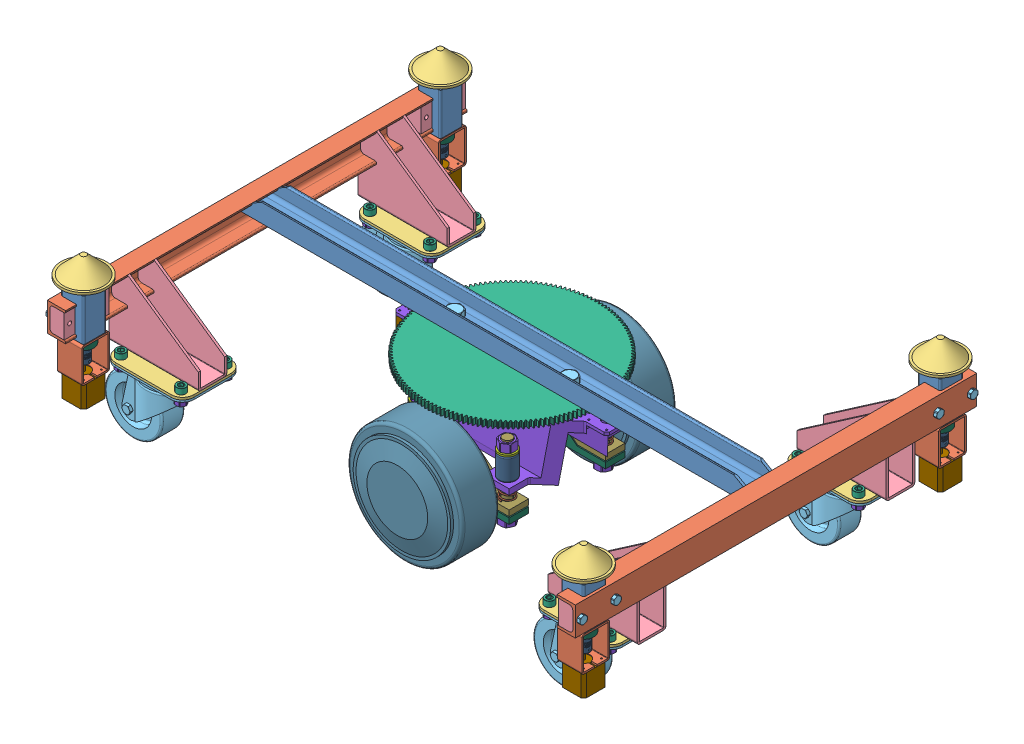
SolidWorks assembly ТП.SH21(K2).00 - Концепт 2, configuration 00. Lengths in mm.
Overall size (950 309 700).
181 component instances, 34 part files, 41 mates.
Components (placement in the parent):
- ТП.SH21(K2).01.00 - Каркас несущий К2-1: ТП.SH21(K2).01.00 - Каркас несущий К2 [00] at (0 265 0) size (950 309 700)
  - ТП.SH21(K2).01.01.00 - Рама силовая (К2)-1: ТП.SH21(K2).01.01.00 - Рама силовая (К2) [00] at origin size (920.8 129.01 700)
    - ТП.SH21(K2).01.01.01 - Хребет продольный-1: ТП.SH21(K2).01.01.01 - Хребет продольный [--] at origin size (912 32 50)
    - ТП.SH21(K2).01.01.02.00 - Балка несущая-1: ТП.SH21(K2).01.01.02.00 - Балка несущая [00] at (-456 -42.75 0) size (155.33 119.25 700)
      - ТП.SH21(K1).01.02 - Поперечина-1: ТП.SH21(K1).01.02 - Поперечина [--] at origin size (32 50 700)
      - ТП.SH21(K2).01.01.02.01.00 - Кронштейн ленивца-1: ТП.SH21(K2).01.01.02.01.00 - Кронштейн ленивца [00] at (82.4347 -94.25 217) size (155.33 119.25 105)
        - ТП.SH21(K1).01.01.02 - Опора ленивца-1: ТП.SH21(K1).01.01.02 - Опора ленивца [--] at origin size (137 4 105)
        - ТП.SH21(K2).01.01.02.01.01 - Касынка кронштейна ленивца-1: ТП.SH21(K2).01.01.02.01.01 - Касынка кронштейна ленивца [--] at (0 4 0) size (155.33 115.25 50)
      - ТП.SH21(K2).01.01.02.01.00 - Кронштейн ленивца-2: ТП.SH21(K2).01.01.02.01.00 - Кронштейн ленивца [00] at (82.4347 -94.25 -217) size (155.33 119.25 105)
        - ТП.SH21(K1).01.01.02 - Опора ленивца-1: ТП.SH21(K1).01.01.02 - Опора ленивца [--] at origin size (137 4 105)
        - ТП.SH21(K2).01.01.02.01.01 - Касынка кронштейна ленивца-1: ТП.SH21(K2).01.01.02.01.01 - Касынка кронштейна ленивца [--] at (0 4 0) size (155.33 115.25 50)
    - ТП.SH21(K2).01.01.02.00 - Балка несущая-2: ТП.SH21(K2).01.01.02.00 - Балка несущая [00] at (456 -42.75 0) x (-1 0 0) z (0 0 -1) size (155.33 119.25 700)
      - ТП.SH21(K1).01.02 - Поперечина-1: ТП.SH21(K1).01.02 - Поперечина [--] at origin size (32 50 700)
      - ТП.SH21(K2).01.01.02.01.00 - Кронштейн ленивца-1: ТП.SH21(K2).01.01.02.01.00 - Кронштейн ленивца [00] at (82.4347 -94.25 217) size (155.33 119.25 105)
        - ТП.SH21(K1).01.01.02 - Опора ленивца-1: ТП.SH21(K1).01.01.02 - Опора ленивца [--] at origin size (137 4 105)
        - ТП.SH21(K2).01.01.02.01.01 - Касынка кронштейна ленивца-1: ТП.SH21(K2).01.01.02.01.01 - Касынка кронштейна ленивца [--] at (0 4 0) size (155.33 115.25 50)
      - ТП.SH21(K2).01.01.02.01.00 - Кронштейн ленивца-2: ТП.SH21(K2).01.01.02.01.00 - Кронштейн ленивца [00] at (82.4347 -94.25 -217) size (155.33 119.25 105)
        - ТП.SH21(K1).01.01.02 - Опора ленивца-1: ТП.SH21(K1).01.01.02 - Опора ленивца [--] at origin size (137 4 105)
        - ТП.SH21(K2).01.01.02.01.01 - Касынка кронштейна ленивца-1: ТП.SH21(K2).01.01.02.01.01 - Касынка кронштейна ленивца [--] at (0 4 0) size (155.33 115.25 50)
  - АЗ - Колесо ленивец - Tente Alpha 3470 ITP 100 P63-1: АЗ - Колесо ленивец - Tente Alpha 3470 ITP 100 P63 [По умолчанию] at (-373.5653 -137 217) size (168.5 128 105)
  - АЗ - Колесо ленивец - Tente Alpha 3470 ITP 100 P63-2: АЗ - Колесо ленивец - Tente Alpha 3470 ITP 100 P63 [По умолчанию] at (373.5653 -137 217) size (168.5 128 105)
  - АЗ - Колесо ленивец - Tente Alpha 3470 ITP 100 P63-3: АЗ - Колесо ленивец - Tente Alpha 3470 ITP 100 P63 [По умолчанию] at (373.5653 -137 -217) size (168.5 128 105)
  - АЗ - Колесо ленивец - Tente Alpha 3470 ITP 100 P63-4: АЗ - Колесо ленивец - Tente Alpha 3470 ITP 100 P63 [По умолчанию] at (-373.5653 -137 -217) size (168.5 128 105)
  - Винты с цилиндрической головкой (ГОСТ 11738-84)-1: Винты с цилиндрической головкой (ГОСТ 11738-84) [Винт М10-(6g)x20 ГОСТ 11738-84] at (-426.0653 -133 255.75) x (0.408379 0 0.912812) z (0 1 0) size (16 16 30.28)
  - Шайбы (ГОСТ 11371-78)-1: Шайбы (ГОСТ 11371-78) [Шайба 10 ГОСТ 11371-78] at (-426.0653 -141.5 255.75) x (0 -1 0) z (0.195759 0 0.980652) size (2 20 20)
  - Гайка (ГОСТ ISO 4032-2014)-1: Гайка (ГОСТ ISO 4032-2014) [Гайка М10 (ГОСТ ISO 4032)] at (-426.0653 -146.7 255.75) x (0.781361 0 0.624079) z (0 1 0) size (16 17.77 8.4)
  - Гайка (ГОСТ ISO 4032-2014)-2: Гайка (ГОСТ ISO 4032-2014) [Гайка М10 (ГОСТ ISO 4032)] at (-321.0653 -146.7 255.75) x (0.884972 0 0.465645) z (0 1 0) size (16 17.77 8.4)
  - Шайбы (ГОСТ 11371-78)-2: Шайбы (ГОСТ 11371-78) [Шайба 10 ГОСТ 11371-78] at (-321.0653 -141.5 255.75) x (0 -1 0) z (0.37706 0 0.926189) size (2 20 20)
  - Винты с цилиндрической головкой (ГОСТ 11738-84)-2: Винты с цилиндрической головкой (ГОСТ 11738-84) [Винт М10-(6g)x20 ГОСТ 11738-84] at (-321.0653 -133 255.75) x (0.573086 0 0.819496) z (0 1 0) size (16 16 30.28)
  - Гайка (ГОСТ ISO 4032-2014)-3: Гайка (ГОСТ ISO 4032-2014) [Гайка М10 (ГОСТ ISO 4032)] at (-321.0653 -146.7 178.25) x (0.964544 0 0.263921) z (0 1 0) size (16 17.77 8.4)
  - Шайбы (ГОСТ 11371-78)-3: Шайбы (ГОСТ 11371-78) [Шайба 10 ГОСТ 11371-78] at (-321.0653 -141.5 178.25) x (0 -1 0) z (0.567856 0 0.823128) size (2 20 20)
  - Винты с цилиндрической головкой (ГОСТ 11738-84)-3: Винты с цилиндрической головкой (ГОСТ 11738-84) [Винт М10-(6g)x20 ГОСТ 11738-84] at (-321.0653 -133 178.25) x (0.736272 0 0.676686) z (0 1 0) size (16 16 30.28)
  - Гайка (ГОСТ ISO 4032-2014)-4: Гайка (ГОСТ ISO 4032-2014) [Гайка М10 (ГОСТ ISO 4032)] at (-426.0653 -146.7 178.25) x (0.999536 0 0.030446) z (0 1 0) size (16 17.77 8.4)
  - Шайбы (ГОСТ 11371-78)-4: Шайбы (ГОСТ 11371-78) [Шайба 10 ГОСТ 11371-78] at (-426.0653 -141.5 178.25) x (0 -1 0) z (0.744998 0 0.667066) size (2 20 20)
  - Винты с цилиндрической головкой (ГОСТ 11738-84)-4: Винты с цилиндрической головкой (ГОСТ 11738-84) [Винт М10-(6g)x20 ГОСТ 11738-84] at (-426.0653 -133 178.25) x (0.874391 0 0.485223) z (0 1 0) size (16 16 30.28)
  - Гайка (ГОСТ ISO 4032-2014)-5: Гайка (ГОСТ ISO 4032-2014) [Гайка М10 (ГОСТ ISO 4032)] at (-426.0653 -146.7 -178.25) x (0.97789 0 -0.209118) z (0 1 0) size (16 17.77 8.4)
  - Шайбы (ГОСТ 11371-78)-5: Шайбы (ГОСТ 11371-78) [Шайба 10 ГОСТ 11371-78] at (-426.0653 -141.5 -178.25) x (0 -1 0) z (0.882737 0 0.469867) size (2 20 20)
  - Винты с цилиндрической головкой (ГОСТ 11738-84)-5: Винты с цилиндрической головкой (ГОСТ 11738-84) [Винт М10-(6g)x20 ГОСТ 11738-84] at (-426.0653 -133 -178.25) x (0.964963 0 0.262386) z (0 1 0) size (16 16 30.28)
  - Гайка (ГОСТ ISO 4032-2014)-6: Гайка (ГОСТ ISO 4032-2014) [Гайка М10 (ГОСТ ISO 4032)] at (-321.0653 -146.7 -178.25) x (0.905941 0 -0.423405) z (0 1 0) size (16 17.77 8.4)
  - Шайбы (ГОСТ 11371-78)-6: Шайбы (ГОСТ 11371-78) [Шайба 10 ГОСТ 11371-78] at (-321.0653 -141.5 -178.25) x (0 -1 0) z (0.965715 0 0.259604) size (2 20 20)
  - Винты с цилиндрической головкой (ГОСТ 11738-84)-6: Винты с цилиндрической головкой (ГОСТ 11738-84) [Винт М10-(6g)x20 ГОСТ 11738-84] at (-321.0653 -133 -178.25) x (0.999241 0 0.038957) z (0 1 0) size (16 16 30.28)
  - Гайка (ГОСТ ISO 4032-2014)-7: Гайка (ГОСТ ISO 4032-2014) [Гайка М10 (ГОСТ ISO 4032)] at (-426.0653 -146.7 -255.75) x (0.807744 0 -0.589534) z (0 1 0) size (16 17.77 8.4)
  - Шайбы (ГОСТ 11371-78)-7: Шайбы (ГОСТ 11371-78) [Шайба 10 ГОСТ 11371-78] at (-426.0653 -141.5 -255.75) x (0 -1 0) z (0.997598 0 0.069276) size (2 20 20)
  - Винты с цилиндрической головкой (ГОСТ 11738-84)-7: Винты с цилиндрической головкой (ГОСТ 11738-84) [Винт М10-(6g)x20 ГОСТ 11738-84] at (-426.0653 -133 -255.75) x (0.988117 0 -0.153703) z (0 1 0) size (16 16 30.28)
  - Гайка (ГОСТ ISO 4032-2014)-8: Гайка (ГОСТ ISO 4032-2014) [Гайка М10 (ГОСТ ISO 4032)] at (-321.0653 -146.7 -255.75) x (0.713458 0 -0.700698) z (0 1 0) size (16 17.77 8.4)
  - Шайбы (ГОСТ 11371-78)-8: Шайбы (ГОСТ 11371-78) [Шайба 10 ГОСТ 11371-78] at (-321.0653 -141.5 -255.75) x (0 -1 0) z (0.997071 0 -0.076488) size (2 20 20)
  - Винты с цилиндрической головкой (ГОСТ 11738-84)-8: Винты с цилиндрической головкой (ГОСТ 11738-84) [Винт М10-(6g)x20 ГОСТ 11738-84] at (-321.0653 -133 -255.75) x (0.955275 0 -0.295719) z (0 1 0) size (16 16 30.28)
  - Гайка (ГОСТ ISO 4032-2014)-9: Гайка (ГОСТ ISO 4032-2014) [Гайка М10 (ГОСТ ISO 4032)] at (321.0653 -146.7 255.75) x (0.647527 0 -0.762043) z (0 1 0) size (16 17.77 8.4)
  - Шайбы (ГОСТ 11371-78)-9: Шайбы (ГОСТ 11371-78) [Шайба 10 ГОСТ 11371-78] at (321.0653 -141.5 255.75) x (0 -1 0) z (0.986146 0 -0.165879) size (2 20 20)
  - Винты с цилиндрической головкой (ГОСТ 11738-84)-9: Винты с цилиндрической головкой (ГОСТ 11738-84) [Винт М10-(6g)x20 ГОСТ 11738-84] at (321.0653 -133 255.75) x (0.924797 0 -0.380462) z (0 1 0) size (16 16 30.28)
  - Гайка (ГОСТ ISO 4032-2014)-10: Гайка (ГОСТ ISO 4032-2014) [Гайка М10 (ГОСТ ISO 4032)] at (426.0653 -146.7 255.75) x (0.624079 0 -0.781361) z (0 1 0) size (16 17.77 8.4)
  - Шайбы (ГОСТ 11371-78)-10: Шайбы (ГОСТ 11371-78) [Шайба 10 ГОСТ 11371-78] at (426.0653 -141.5 255.75) x (0 -1 0) z (0.980652 0 -0.195759) size (2 20 20)
  - Винты с цилиндрической головкой (ГОСТ 11738-84)-10: Винты с цилиндрической головкой (ГОСТ 11738-84) [Винт М10-(6g)x20 ГОСТ 11738-84] at (426.0653 -133 255.75) x (0.912812 0 -0.408379) z (0 1 0) size (16 16 30.28)
  - Гайка (ГОСТ ISO 4032-2014)-11: Гайка (ГОСТ ISO 4032-2014) [Гайка М10 (ГОСТ ISO 4032)] at (321.0653 -146.7 178.25) x (0.647527 0 -0.762043) z (0 1 0) size (16 17.77 8.4)
  - Шайбы (ГОСТ 11371-78)-11: Шайбы (ГОСТ 11371-78) [Шайба 10 ГОСТ 11371-78] at (321.0653 -141.5 178.25) x (0 -1 0) z (0.986146 0 -0.165879) size (2 20 20)
  - Винты с цилиндрической головкой (ГОСТ 11738-84)-11: Винты с цилиндрической головкой (ГОСТ 11738-84) [Винт М10-(6g)x20 ГОСТ 11738-84] at (321.0653 -133 178.25) x (0.924797 0 -0.380462) z (0 1 0) size (16 16 30.28)
  - Гайка (ГОСТ ISO 4032-2014)-12: Гайка (ГОСТ ISO 4032-2014) [Гайка М10 (ГОСТ ISO 4032)] at (426.0653 -146.7 178.25) x (0.713458 0 -0.700698) z (0 1 0) size (16 17.77 8.4)
  - Шайбы (ГОСТ 11371-78)-12: Шайбы (ГОСТ 11371-78) [Шайба 10 ГОСТ 11371-78] at (426.0653 -141.5 178.25) x (0 -1 0) z (0.997071 0 -0.076488) size (2 20 20)
  - Винты с цилиндрической головкой (ГОСТ 11738-84)-12: Винты с цилиндрической головкой (ГОСТ 11738-84) [Винт М10-(6g)x20 ГОСТ 11738-84] at (426.0653 -133 178.25) x (0.955275 0 -0.295719) z (0 1 0) size (16 16 30.28)
  - Гайка (ГОСТ ISO 4032-2014)-13: Гайка (ГОСТ ISO 4032-2014) [Гайка М10 (ГОСТ ISO 4032)] at (321.0653 -146.7 -178.25) x (0.807744 0 -0.589534) z (0 1 0) size (16 17.77 8.4)
  - Шайбы (ГОСТ 11371-78)-13: Шайбы (ГОСТ 11371-78) [Шайба 10 ГОСТ 11371-78] at (321.0653 -141.5 -178.25) x (0 -1 0) z (0.997598 0 0.069276) size (2 20 20)
  - Винты с цилиндрической головкой (ГОСТ 11738-84)-13: Винты с цилиндрической головкой (ГОСТ 11738-84) [Винт М10-(6g)x20 ГОСТ 11738-84] at (321.0653 -133 -178.25) x (0.988117 0 -0.153703) z (0 1 0) size (16 16 30.28)
  - Гайка (ГОСТ ISO 4032-2014)-14: Гайка (ГОСТ ISO 4032-2014) [Гайка М10 (ГОСТ ISO 4032)] at (426.0653 -146.7 -178.25) x (0.905941 0 -0.423405) z (0 1 0) size (16 17.77 8.4)
  - Шайбы (ГОСТ 11371-78)-14: Шайбы (ГОСТ 11371-78) [Шайба 10 ГОСТ 11371-78] at (426.0653 -141.5 -178.25) x (0 -1 0) z (0.965715 0 0.259604) size (2 20 20)
  - Винты с цилиндрической головкой (ГОСТ 11738-84)-14: Винты с цилиндрической головкой (ГОСТ 11738-84) [Винт М10-(6g)x20 ГОСТ 11738-84] at (426.0653 -133 -178.25) x (0.999241 0 0.038957) z (0 1 0) size (16 16 30.28)
  - Гайка (ГОСТ ISO 4032-2014)-15: Гайка (ГОСТ ISO 4032-2014) [Гайка М10 (ГОСТ ISO 4032)] at (321.0653 -146.7 -255.75) x (0.97789 0 -0.209118) z (0 1 0) size (16 17.77 8.4)
  - Шайбы (ГОСТ 11371-78)-15: Шайбы (ГОСТ 11371-78) [Шайба 10 ГОСТ 11371-78] at (321.0653 -141.5 -255.75) x (0 -1 0) z (0.882737 0 0.469867) size (2 20 20)
  - Винты с цилиндрической головкой (ГОСТ 11738-84)-15: Винты с цилиндрической головкой (ГОСТ 11738-84) [Винт М10-(6g)x20 ГОСТ 11738-84] at (321.0653 -133 -255.75) x (0.964963 0 0.262386) z (0 1 0) size (16 16 30.28)
  - Гайка (ГОСТ ISO 4032-2014)-16: Гайка (ГОСТ ISO 4032-2014) [Гайка М10 (ГОСТ ISO 4032)] at (426.0653 -146.7 -255.75) x (0.999536 0 0.030446) z (0 1 0) size (16 17.77 8.4)
  - Шайбы (ГОСТ 11371-78)-16: Шайбы (ГОСТ 11371-78) [Шайба 10 ГОСТ 11371-78] at (426.0653 -141.5 -255.75) x (0 -1 0) z (0.744998 0 0.667066) size (2 20 20)
  - Винты с цилиндрической головкой (ГОСТ 11738-84)-16: Винты с цилиндрической головкой (ГОСТ 11738-84) [Винт М10-(6g)x20 ГОСТ 11738-84] at (426.0653 -133 -255.75) x (0.874391 0 0.485223) z (0 1 0) size (16 16 30.28)
  - ТП.SH21(K1).02.00 - Линейный движитель-1: ТП.SH21(K1).02.00 - Линейный движитель [00] at (-436 -133 311) x (1 0 0) z (0 1 0) size (78 78 215)
    - 17HS4401 (Nema17)-1: 17HS4401 (Nema17) [--] at origin size (42.3 42.3 63.5)
    - Муфта гибкая-1: Муфта гибкая [--] at (0 0 42.25) size (20 20 26)
    - Винт CS М12х2х150-1: Винт CS М12х2х150 [--] at (0 0 133) x (0.999367 0.035585 0) z (0 0 1) size (12 12.62 100)
    - ТП.SH21(K1).02.01 - Упор винта-1: ТП.SH21(K1).02.01 - Упор винта [--] at (0 0 57.25) size (14 14 13)
    - Подшипник упорный 8100-1: Подшипник упорный 8100 [--] at (0 0 48.25) x (1 0 0) z (0 -1 0) size (24 9 24)
    - Стопор внутренний до 165мм (ГОСТ 13943-86)-1: Стопор внутренний до 165мм (ГОСТ 13943-86) [Кольцо 24] at (0 0 47.05) size (25.5 24.21 1.2)
    - ТП.SH21(K1).02.02 - Обойма под 8100-1: ТП.SH21(K1).02.02 - Обойма под 8100 [--] at (0 0 48.25) size (35 35 16.2)
    - Гайка DCM12-1: Гайка DCM12 [Доработка] at (0 0 64.25) x (0 0 1) z (-0.707107 -0.707107 0) size (30.72 41.36 41.36)
    - ТП.SH21(K1).02.03 - Профильная труба 35х35х2-1: ТП.SH21(K1).02.03 - Профильная труба 35х35х2 [--] at (0 0 74.25) size (35 35 68.75)
    - ТП.SH21(K1).02.04 - Заглушка35х35-1: ТП.SH21(K1).02.04 - Заглушка35х35 [--] at (0 0 70.25) size (35 35 4)
    - ТП.SH21(K1).02.05 - Профильная труба 40х40х2-1: ТП.SH21(K1).02.05 - Профильная труба 40х40х2 [--] at (0 0 60.25) size (40 40 72.75)
    - ТП.SH21(K1).02.06 - Заглушка 40х40-1: ТП.SH21(K1).02.06 - Заглушка 40х40 [--] at (0 0 60.25) size (42.3 48.3 60.25)
    - ТП.SH21(K1).02.07 - Уловитель-1: ТП.SH21(K1).02.07 - Уловитель [--] at (0 0 143) size (78 78 39)
    - ТП.SH21(K1).02.08 - Фиксатор-1: ТП.SH21(K1).02.08 - Фиксатор [--] at (-20 -20 60.25) x (0 1 0) z (1 0 0) size (19 41.2 25.1)
    - ТП.SH21(K1).02.08 - Фиксатор-2: ТП.SH21(K1).02.08 - Фиксатор [--] at (-20 39 60.25) x (0 1 0) z (1 0 0) size (19 41.2 25.1)
  - Болты с шестигранной головкой кт.В (ГОСТ 7798-70)-1: Болты с шестигранной головкой кт.В (ГОСТ 7798-70) [Болт М8-6gx25(S13) ГОСТ 7798-77] at (-460.4 -42.75 340.5) size (30.3 14.2 13)
  - Болты с шестигранной головкой кт.В (ГОСТ 7798-70)-2: Болты с шестигранной головкой кт.В (ГОСТ 7798-70) [Болт М8-6gx25(S13) ГОСТ 7798-77] at (-460.4 -42.75 281.5) x (1 0 0) z (0 -0.158553 0.987351) size (30.3 14.2 13)
  - ТП.SH21(K1).02.00 - Линейный движитель-2: ТП.SH21(K1).02.00 - Линейный движитель [00] at (-436 -133 -311) x (1 0 0) z (0 1 0) size (78 78 215)
    - 17HS4401 (Nema17)-1: 17HS4401 (Nema17) [--] at origin size (42.3 42.3 63.5)
    - Муфта гибкая-1: Муфта гибкая [--] at (0 0 42.25) size (20 20 26)
    - Винт CS М12х2х150-1: Винт CS М12х2х150 [--] at (0 0 133) x (0.999367 0.035585 0) z (0 0 1) size (12 12.62 100)
    - ТП.SH21(K1).02.01 - Упор винта-1: ТП.SH21(K1).02.01 - Упор винта [--] at (0 0 57.25) size (14 14 13)
    - Подшипник упорный 8100-1: Подшипник упорный 8100 [--] at (0 0 48.25) x (1 0 0) z (0 -1 0) size (24 9 24)
    - Стопор внутренний до 165мм (ГОСТ 13943-86)-1: Стопор внутренний до 165мм (ГОСТ 13943-86) [Кольцо 24] at (0 0 47.05) size (25.5 24.21 1.2)
    - ТП.SH21(K1).02.02 - Обойма под 8100-1: ТП.SH21(K1).02.02 - Обойма под 8100 [--] at (0 0 48.25) size (35 35 16.2)
    - Гайка DCM12-1: Гайка DCM12 [Доработка] at (0 0 64.25) x (0 0 1) z (-0.707107 -0.707107 0) size (30.72 41.36 41.36)
    - ТП.SH21(K1).02.03 - Профильная труба 35х35х2-1: ТП.SH21(K1).02.03 - Профильная труба 35х35х2 [--] at (0 0 74.25) size (35 35 68.75)
    - ТП.SH21(K1).02.04 - Заглушка35х35-1: ТП.SH21(K1).02.04 - Заглушка35х35 [--] at (0 0 70.25) size (35 35 4)
    - ТП.SH21(K1).02.05 - Профильная труба 40х40х2-1: ТП.SH21(K1).02.05 - Профильная труба 40х40х2 [--] at (0 0 60.25) size (40 40 72.75)
    - ТП.SH21(K1).02.06 - Заглушка 40х40-1: ТП.SH21(K1).02.06 - Заглушка 40х40 [--] at (0 0 60.25) size (42.3 48.3 60.25)
    - ТП.SH21(K1).02.07 - Уловитель-1: ТП.SH21(K1).02.07 - Уловитель [--] at (0 0 143) size (78 78 39)
    - ТП.SH21(K1).02.08 - Фиксатор-1: ТП.SH21(K1).02.08 - Фиксатор [--] at (-20 -20 60.25) x (0 1 0) z (1 0 0) size (19 41.2 25.1)
    - ТП.SH21(K1).02.08 - Фиксатор-2: ТП.SH21(K1).02.08 - Фиксатор [--] at (-20 39 60.25) x (0 1 0) z (1 0 0) size (19 41.2 25.1)
  - Болты с шестигранной головкой кт.В (ГОСТ 7798-70)-4: Болты с шестигранной головкой кт.В (ГОСТ 7798-70) [Болт М8-6gx25(S13) ГОСТ 7798-77] at (-460.4 -42.75 -281.5) size (30.3 14.2 13)
  - Болты с шестигранной головкой кт.В (ГОСТ 7798-70)-5: Болты с шестигранной головкой кт.В (ГОСТ 7798-70) [Болт М8-6gx25(S13) ГОСТ 7798-77] at (-460.4 -42.75 -340.5) x (1 0 0) z (0 -0.158553 0.987351) size (30.3 14.2 13)
  - ТП.SH21(K1).02.00 - Линейный движитель-5: ТП.SH21(K1).02.00 - Линейный движитель [00] at (436 -133 311) x (-1 0 0) z (0 1 0) size (78 78 215)
    - 17HS4401 (Nema17)-1: 17HS4401 (Nema17) [--] at origin size (42.3 42.3 63.5)
    - Муфта гибкая-1: Муфта гибкая [--] at (0 0 42.25) size (20 20 26)
    - Винт CS М12х2х150-1: Винт CS М12х2х150 [--] at (0 0 133) x (0.999367 0.035585 0) z (0 0 1) size (12 12.62 100)
    - ТП.SH21(K1).02.01 - Упор винта-1: ТП.SH21(K1).02.01 - Упор винта [--] at (0 0 57.25) size (14 14 13)
    - Подшипник упорный 8100-1: Подшипник упорный 8100 [--] at (0 0 48.25) x (1 0 0) z (0 -1 0) size (24 9 24)
    - Стопор внутренний до 165мм (ГОСТ 13943-86)-1: Стопор внутренний до 165мм (ГОСТ 13943-86) [Кольцо 24] at (0 0 47.05) size (25.5 24.21 1.2)
    - ТП.SH21(K1).02.02 - Обойма под 8100-1: ТП.SH21(K1).02.02 - Обойма под 8100 [--] at (0 0 48.25) size (35 35 16.2)
    - Гайка DCM12-1: Гайка DCM12 [Доработка] at (0 0 64.25) x (0 0 1) z (-0.707107 -0.707107 0) size (30.72 41.36 41.36)
    - ТП.SH21(K1).02.03 - Профильная труба 35х35х2-1: ТП.SH21(K1).02.03 - Профильная труба 35х35х2 [--] at (0 0 74.25) size (35 35 68.75)
    - ТП.SH21(K1).02.04 - Заглушка35х35-1: ТП.SH21(K1).02.04 - Заглушка35х35 [--] at (0 0 70.25) size (35 35 4)
    - ТП.SH21(K1).02.05 - Профильная труба 40х40х2-1: ТП.SH21(K1).02.05 - Профильная труба 40х40х2 [--] at (0 0 60.25) size (40 40 72.75)
    - ТП.SH21(K1).02.06 - Заглушка 40х40-1: ТП.SH21(K1).02.06 - Заглушка 40х40 [--] at (0 0 60.25) size (42.3 48.3 60.25)
    - ТП.SH21(K1).02.07 - Уловитель-1: ТП.SH21(K1).02.07 - Уловитель [--] at (0 0 143) size (78 78 39)
    - ТП.SH21(K1).02.08 - Фиксатор-1: ТП.SH21(K1).02.08 - Фиксатор [--] at (-20 -20 60.25) x (0 1 0) z (1 0 0) size (19 41.2 25.1)
    - ТП.SH21(K1).02.08 - Фиксатор-2: ТП.SH21(K1).02.08 - Фиксатор [--] at (-20 39 60.25) x (0 1 0) z (1 0 0) size (19 41.2 25.1)
  - Болты с шестигранной головкой кт.В (ГОСТ 7798-70)-10: Болты с шестигранной головкой кт.В (ГОСТ 7798-70) [Болт М8-6gx25(S13) ГОСТ 7798-77] at (460.4 -42.75 281.5) x (-1 0 0) z (0 0 -1) size (30.3 14.2 13)
  - Болты с шестигранной головкой кт.В (ГОСТ 7798-70)-11: Болты с шестигранной головкой кт.В (ГОСТ 7798-70) [Болт М8-6gx25(S13) ГОСТ 7798-77] at (460.4 -42.75 340.5) x (-1 0 0) z (0 -0.158553 -0.987351) size (30.3 14.2 13)
  - ТП.SH21(K1).02.00 - Линейный движитель-7: ТП.SH21(K1).02.00 - Линейный движитель [00] at (436 -133 -311) x (-1 0 0) z (0 1 0) size (78 78 215)
    - 17HS4401 (Nema17)-1: 17HS4401 (Nema17) [--] at origin size (42.3 42.3 63.5)
    - Муфта гибкая-1: Муфта гибкая [--] at (0 0 42.25) size (20 20 26)
    - Винт CS М12х2х150-1: Винт CS М12х2х150 [--] at (0 0 133) x (0.999367 0.035585 0) z (0 0 1) size (12 12.62 100)
    - ТП.SH21(K1).02.01 - Упор винта-1: ТП.SH21(K1).02.01 - Упор винта [--] at (0 0 57.25) size (14 14 13)
    - Подшипник упорный 8100-1: Подшипник упорный 8100 [--] at (0 0 48.25) x (1 0 0) z (0 -1 0) size (24 9 24)
    - Стопор внутренний до 165мм (ГОСТ 13943-86)-1: Стопор внутренний до 165мм (ГОСТ 13943-86) [Кольцо 24] at (0 0 47.05) size (25.5 24.21 1.2)
    - ТП.SH21(K1).02.02 - Обойма под 8100-1: ТП.SH21(K1).02.02 - Обойма под 8100 [--] at (0 0 48.25) size (35 35 16.2)
    - Гайка DCM12-1: Гайка DCM12 [Доработка] at (0 0 64.25) x (0 0 1) z (-0.707107 -0.707107 0) size (30.72 41.36 41.36)
    - ТП.SH21(K1).02.03 - Профильная труба 35х35х2-1: ТП.SH21(K1).02.03 - Профильная труба 35х35х2 [--] at (0 0 74.25) size (35 35 68.75)
    - ТП.SH21(K1).02.04 - Заглушка35х35-1: ТП.SH21(K1).02.04 - Заглушка35х35 [--] at (0 0 70.25) size (35 35 4)
    - ТП.SH21(K1).02.05 - Профильная труба 40х40х2-1: ТП.SH21(K1).02.05 - Профильная труба 40х40х2 [--] at (0 0 60.25) size (40 40 72.75)
    - ТП.SH21(K1).02.06 - Заглушка 40х40-1: ТП.SH21(K1).02.06 - Заглушка 40х40 [--] at (0 0 60.25) size (42.3 48.3 60.25)
    - ТП.SH21(K1).02.07 - Уловитель-1: ТП.SH21(K1).02.07 - Уловитель [--] at (0 0 143) size (78 78 39)
    - ТП.SH21(K1).02.08 - Фиксатор-1: ТП.SH21(K1).02.08 - Фиксатор [--] at (-20 -20 60.25) x (0 1 0) z (1 0 0) size (19 41.2 25.1)
    - ТП.SH21(K1).02.08 - Фиксатор-2: ТП.SH21(K1).02.08 - Фиксатор [--] at (-20 39 60.25) x (0 1 0) z (1 0 0) size (19 41.2 25.1)
  - Болты с шестигранной головкой кт.В (ГОСТ 7798-70)-14: Болты с шестигранной головкой кт.В (ГОСТ 7798-70) [Болт М8-6gx25(S13) ГОСТ 7798-77] at (460.4 -42.75 -340.5) x (-1 0 0) z (0 0 -1) size (30.3 14.2 13)
  - Болты с шестигранной головкой кт.В (ГОСТ 7798-70)-15: Болты с шестигранной головкой кт.В (ГОСТ 7798-70) [Болт М8-6gx25(S13) ГОСТ 7798-77] at (460.4 -42.75 -281.5) x (-1 0 0) z (0 -0.158553 -0.987351) size (30.3 14.2 13)
  - ТП.SH21(K2).01.02 - Шестерня большая-2: ТП.SH21(K2).01.02 - Шестерня большая [Z150] at (0 -39.99 0) x (0 -1 0) z (0 0 1) size (87 303.96 304)
  - Болты с шестигранной головкой кт.В (ГОСТ 7798-70)-18: Болты с шестигранной головкой кт.В (ГОСТ 7798-70) [*Болт М16-6gx18(S24) ГОСТ 7798-77] at (100 -35.59 0) x (0 -1 0) z (0.995564 0 -0.094084) size (28 26.2 24)
  - Болты с шестигранной головкой кт.В (ГОСТ 7798-70)-19: Болты с шестигранной головкой кт.В (ГОСТ 7798-70) [*Болт М16-6gx18(S24) ГОСТ 7798-77] at (-100 -35.59 0) x (0 -1 0) z (0.959995 0 -0.280017) size (28 26.2 24)
- Подшипник 2007910А (72х50х15)-1: Подшипник 2007910А (72х50х15) [--] at (0 202.01 0) x (0 1 0) z (-0.845753 0 0.533575) size (15 72 72)
- ТП.SH21(K2).02.00 - Кронштейн ступицы поворотной-1: ТП.SH21(K2).02.00 - Кронштейн ступицы поворотной [00] at (0 199.51 0) size (372.3 178 210.07)
  - ТП.SH21(K2).02.01 - Каретка-1: ТП.SH21(K2).02.01 - Каретка [--] at origin size (372.3 98.5 202)
  - ТП.SH21(K2).02.02 - Обойма 2007910А (2шт)-1: ТП.SH21(K2).02.02 - Обойма 2007910А (2шт) [--] at (0 -2.5 0) x (0 -1 0) z (-0.634197 0 -0.773171) size (47 82 82)
  - Линейный подшипник (16х30х40)-1: Линейный подшипник (16х30х40) [--] at (-76 -63.5 84) x (-0.966713 0 0.255864) z (0 -1 0) size (30 30 40)
  - Линейный подшипник (16х30х40)-2: Линейный подшипник (16х30х40) [--] at (76 -63.5 84) x (-0.901172 0 0.433461) z (0 -1 0) size (30 30 40)
  - Линейный подшипник (16х30х40)-3: Линейный подшипник (16х30х40) [--] at (76 -63.5 -84) x (-0.786541 0 0.617538) z (0 -1 0) size (30 30 40)
  - Линейный подшипник (16х30х40)-4: Линейный подшипник (16х30х40) [--] at (-76 -63.5 -84) x (-0.619852 0 0.784719) z (0 -1 0) size (30 30 40)
  - ТП.SH21(K1).01.03 - Пружина 22х22х2-1: ТП.SH21(K1).01.03 - Пружина 22х22х2 [--] at (76 -93.75 -84) x (-0.837169 0 -0.546944) z (-0.546944 0 0.837169) size (24 22 24.59)
  - ТП.SH21(K1).01.03 - Пружина 22х22х2-2: ТП.SH21(K1).01.03 - Пружина 22х22х2 [--] at (-76 -93.75 -84) x (-0.925243 0 -0.379375) z (-0.379375 0 0.925243) size (24 22 24.59)
  - ТП.SH21(K1).01.03 - Пружина 22х22х2-3: ТП.SH21(K1).01.03 - Пружина 22х22х2 [--] at (-76 -93.75 84) x (-0.985271 0 -0.170998) z (-0.170998 0 0.985271) size (24 22 24.59)
  - ТП.SH21(K1).01.03 - Пружина 22х22х2-4: ТП.SH21(K1).01.03 - Пружина 22х22х2 [--] at (76 -93.75 84) x (-0.997902 0 0.064746) z (0.064746 0 0.997902) size (24 22 24.59)
  - ТП.SH21(K2).02.03 - Верхний кронштейн К2-1: ТП.SH21(K2).02.03 - Верхний кронштейн К2 [--] at (0 -99.5 -67) size (192 129 34)
  - ТП.SH21(K2).02.03 - Верхний кронштейн К2-2: ТП.SH21(K2).02.03 - Верхний кронштейн К2 [--] at (0 -99.5 101) size (192 129 34)
  - Шайбы (ГОСТ 11371-78)-1: Шайбы (ГОСТ 11371-78) [Шайба 16 ГОСТ 11371-78] at (76 -42 -84) x (0 -1 0) z (0 0 1) size (3 30 30)
  - Гайка (ГОСТ ISO 4032-2014)-1: Гайка (ГОСТ ISO 4032-2014) [Гайка М16 (ГОСТ ISO 4032)] at (76 -33.1 -84) x (0.816213 0 0.577751) z (0 1 0) size (24 26.75 14.8)
  - Гайка (ГОСТ ISO 4032-2014)-2: Гайка (ГОСТ ISO 4032-2014) [Гайка М16 (ГОСТ ISO 4032)] at (-76 -33.1 -84) x (0.910468 0 0.413579) z (0 1 0) size (24 26.75 14.8)
  - Шайбы (ГОСТ 11371-78)-2: Шайбы (ГОСТ 11371-78) [Шайба 16 ГОСТ 11371-78] at (-76 -42 -84) x (0 -1 0) z (0.188455 0 0.982082) size (3 30 30)
  - Гайка (ГОСТ ISO 4032-2014)-4: Гайка (ГОСТ ISO 4032-2014) [Гайка М16 (ГОСТ ISO 4032)] at (-76 -33.1 84) x (0.978217 0 0.207583) z (0 1 0) size (24 26.75 14.8)
  - Шайбы (ГОСТ 11371-78)-4: Шайбы (ГОСТ 11371-78) [Шайба 16 ГОСТ 11371-78] at (-76 -42 84) x (0 -1 0) z (0.395734 0 0.918365) size (3 30 30)
  - Гайка (ГОСТ ISO 4032-2014)-6: Гайка (ГОСТ ISO 4032-2014) [Гайка М16 (ГОСТ ISO 4032)] at (76 -33.1 84) x (0.999621 0 -0.027527) z (0 1 0) size (24 26.75 14.8)
  - Шайбы (ГОСТ 11371-78)-6: Шайбы (ГОСТ 11371-78) [Шайба 16 ГОСТ 11371-78] at (76 -42 84) x (0 -1 0) z (0.6 0 0.8) size (3 30 30)
  - 17HS4401 (Nema17)-1: 17HS4401 (Nema17) [--] at (-165 0 0) x (1 0 0) z (0 1 0) size (42.3 42.3 63.5)
- ТП.SH21(K2).03 - Шестерня малая-4: ТП.SH21(K2).03 - Шестерня малая [DIN - Spur gear 2M 15T 20PA 10FW ---S15B15H23L5N] at (-165 215.01 0) x (0 1 0) z (0.147192 0 0.989108) size (23 33.72 33.9)
- Мотор-колесо ZLLG80ASM800-2: Мотор-колесо ZLLG80ASM800 [1 крепление] at (0 100.01 154.5) x (0 0 1) z (0 1 0) size (133 200 200)
- ТП.SH21(K2).04 - Прижим К2-1: ТП.SH21(K2).04 - Прижим К2 [--] at (0 100.01 101) size (192 37 34)
- Гайка (ГОСТ ISO 4032-2014)-1: Гайка (ГОСТ ISO 4032-2014) [Гайка М16 (ГОСТ ISO 4032)] at (76 54.61 84) x (-0.815496 0 0.578763) z (0 -1 0) size (24 26.75 14.8)
- Гайка (ГОСТ ISO 4032-2014)-2: Гайка (ГОСТ ISO 4032-2014) [Гайка М16 (ГОСТ ISO 4032)] at (-76 54.61 84) x (-0.691813 0 0.722077) z (0 -1 0) size (24 26.75 14.8)
- Гайка (ГОСТ ISO 4032-2014)-5: Гайка (ГОСТ ISO 4032-2014) [Гайка М16 (ГОСТ ISO 4032)] at (-76 54.61 -84) x (-0.691813 0 0.722077) z (0 -1 0) size (24 26.75 14.8)
- ТП.SH21(K2).04 - Прижим К2-2: ТП.SH21(K2).04 - Прижим К2 [--] at (0 100.01 -67) size (192 37 34)
- Мотор-колесо ZLLG80ASM800-3: Мотор-колесо ZLLG80ASM800 [1 крепление] at (0 100.01 -154.5) x (0 0 -1) z (0 1 0) size (133 200 200)
- Гайка (ГОСТ ISO 4032-2014)-6: Гайка (ГОСТ ISO 4032-2014) [Гайка М16 (ГОСТ ISO 4032)] at (76 54.61 -84) x (-0.815496 0 0.578763) z (0 -1 0) size (24 26.75 14.8)
- Подшипник 2007910А (72х50х15)-2: Подшипник 2007910А (72х50х15) [--] at (0 197.01 0) x (0 -1 0) z (-0.971836 0 0.235658) size (15 72 72)
- ТП.SH21(K2).05 - Кольцо ступицы-1: ТП.SH21(K2).05 - Кольцо ступицы [--] at (0 177.01 0) x (-0.975842 0 0.218478) z (0.218478 0 0.975842) size (61.75 5 61.75)
- Гайка (ГОСТ ISO 4032-2014)-9: Гайка (ГОСТ ISO 4032-2014) [Гайка М42 (ГОСТ ISO 4032)] at (0 160.01 0) x (-0.987419 0 0.158123) z (0 -1 0) size (65 71.3 34)
Mates (geometry in assembly coordinates):
- Касательность1: tangent: cylinder of ТП.SH21(K2).01.00 - Каркас несущий К2-1/АЗ - Колесо ленивец - Tente Alpha 3470 ITP 100 P63-2 through (323.5653 50 197) axis (0 0 1) radius 50; plane of assembly through (0 0 0) normal (0 1 0)
- Параллельность1: parallel: plane of ТП.SH21(K2).01.00 - Каркас несущий К2-1/ТП.SH21(K2).01.02 - Шестерня большая-2 through (0 225.01 0) normal (0 1 0); plane of assembly
- Совпадение1: coincident: plane of ТП.SH21(K2).01.00 - Каркас несущий К2-1/ТП.SH21(K2).01.01.00 - Рама силовая (К2)-1/ТП.SH21(K2).01.01.01 - Хребет продольный-1 through (0 265 0) normal (0 0 1); plane of assembly through (0 0 0) normal (0 0 1)
- Совпадение2: coincident: plane of ТП.SH21(K2).01.00 - Каркас несущий К2-1/ТП.SH21(K2).01.01.00 - Рама силовая (К2)-1/ТП.SH21(K2).01.01.01 - Хребет продольный-1 through (0 265 0) normal (1 0 0); plane of assembly through (0 0 0) normal (1 0 0)
- Совпадение3: coincident: plane of ТП.SH21(K2).01.00 - Каркас несущий К2-1/ТП.SH21(K2).01.02 - Шестерня большая-2 through (13.1971 217.01 -31.9421) normal (0 -1 0); plane of Подшипник 2007910А (72х50х15)-1 through (-18.4409 217.01 -29.2301) normal (0 1 0)
- Концентричный1: concentric: cylinder of Подшипник 2007910А (72х50х15)-1 through (0 -797.99 0) axis (0 -1 0) radius 25; cylinder of ТП.SH21(K2).01.00 - Каркас несущий К2-1/ТП.SH21(K2).01.02 - Шестерня большая-2 through (0 111.2993 0) axis (0 1 0) radius 25
- Совпадение4: coincident: plane of Подшипник 2007910А (72х50х15)-1 through (-18.8885 202.01 -29.9397) normal (0 -1 0); plane of ТП.SH21(K2).02.00 - Кронштейн ступицы поворотной-1/ТП.SH21(K2).02.02 - Обойма 2007910А (2шт)-1 through (-27.8342 202.01 22.8311) normal (0 1 0)
- Концентричный2: concentric: cylinder of Подшипник 2007910А (72х50х15)-1 through (0 -797.99 0) axis (0 -1 0) radius 36; cylinder of ТП.SH21(K2).02.00 - Кронштейн ступицы поворотной-1/ТП.SH21(K2).02.02 - Обойма 2007910А (2шт)-1 through (0 1197.01 0) axis (0 1 0) radius 36
- Совпадение5: coincident: plane of ТП.SH21(K2).02.00 - Кронштейн ступицы поворотной-1/17HS4401 (Nema17)-1 through (-165 225.01 0) normal (0 1 0); plane of ТП.SH21(K2).03 - Шестерня малая-4 through (-165 225.01 0) normal (0 1 0)
- Концентричный3: concentric: cylinder of ТП.SH21(K2).02.00 - Кронштейн ступицы поворотной-1/17HS4401 (Nema17)-1 through (-165 225.01 0) axis (0 -1 0) radius 2.5; cylinder of ТП.SH21(K2).03 - Шестерня малая-4 through (-165 238.0101 0) axis (0 -1 0) radius 2.5
- Совпадение6: coincident: plane of ТП.SH21(K2).02.00 - Кронштейн ступицы поворотной-1/ТП.SH21(K2).02.03 - Верхний кронштейн К2-1 through (177.7485 106.01 -103.8322) normal (0 -1 0); plane of ? through (-140437.6755 106.01 -255540.1748) normal (0 1 0)
- Совпадение7: coincident: plane of ТП.SH21(K2).02.00 - Кронштейн ступицы поворотной-1/ТП.SH21(K2).02.03 - Верхний кронштейн К2-1; plane of ? through (88.4913 100.01 -48.6857) normal (-0.876151 0 0.482036)
- Концентричный4: concentric: cylinder of ТП.SH21(K2).02.00 - Кронштейн ступицы поворотной-1/ТП.SH21(K2).02.03 - Верхний кронштейн К2-1 through (180.2992 100.01 -99.1961) axis (-0.876151 0 0.482036) radius 8; cylinder of ? through (1006.1753 100.01 -553.5723) axis (0.876151 0 -0.482036) radius 8
- Угол1: planar angle = 0 rad: plane of ТП.SH21(K2).02.00 - Кронштейн ступицы поворотной-1/ТП.SH21(K2).02.03 - Верхний кронштейн К2-2 through (0 100.01 101) normal (0 0 1); plane of ТП.SH21(K2).01.00 - Каркас несущий К2-1/ТП.SH21(K2).01.01.00 - Рама силовая (К2)-1/ТП.SH21(K2).01.01.01 - Хребет продольный-1 through (-515.3633 225.01 25) normal (0 0 1)
- Концентричный5: concentric: cylinder of ТП.SH21(K2).02.00 - Кронштейн ступицы поворотной-1/ТП.SH21(K2).02.03 - Верхний кронштейн К2-2 through (0 100.01 -37.7855) axis (0 0 1) radius 8; cylinder of Мотор-колесо ZLLG80ASM800-2 through (0 100.01 -946.4037) axis (0 0 -1) radius 8
- Совпадение8: coincident: plane of ТП.SH21(K2).02.00 - Кронштейн ступицы поворотной-1/ТП.SH21(K2).02.03 - Верхний кронштейн К2-2 through (-5.2915 106.01 -37.7855) normal (0 -1 0); plane of Мотор-колесо ZLLG80ASM800-2 through (-291587.9 106.01 67) normal (0 1 0)
- Совпадение9: coincident: plane of ТП.SH21(K2).02.00 - Кронштейн ступицы поворотной-1/ТП.SH21(K2).02.03 - Верхний кронштейн К2-2 through (0 100.01 101) normal (0 0 1); plane of Мотор-колесо ZLLG80ASM800-2 through (0 100.01 101) normal (0 0 -1)
- Совпадение10: coincident: plane of Мотор-колесо ZLLG80ASM800-2 through (-291587.9 94.01 67) normal (0 -1 0); plane of ТП.SH21(K2).04 - Прижим К2-1 through (0 94.01 -37.7855) normal (0 1 0)
- Концентричный6: concentric: cylinder of ТП.SH21(K2).02.00 - Кронштейн ступицы поворотной-1/ТП.SH21(K2).02.03 - Верхний кронштейн К2-2 through (-76 218.6374 84) axis (0 -1 0) radius 8; cylinder of ТП.SH21(K2).04 - Прижим К2-1 through (-76 96.0516 84) axis (0 -1 0) radius 8.5
- Концентричный7: concentric: cylinder of ТП.SH21(K2).02.00 - Кронштейн ступицы поворотной-1/ТП.SH21(K2).02.03 - Верхний кронштейн К2-2 through (76 218.6374 84) axis (0 -1 0) radius 8; cylinder of ТП.SH21(K2).04 - Прижим К2-1 through (76 96.0516 84) axis (0 -1 0) radius 8.5
- Совпадение11: coincident: plane of ТП.SH21(K2).04 - Прижим К2-1 through (0 62.01 -37.7855) normal (0 -1 0); plane of Гайка (ГОСТ ISO 4032-2014)-1 through (69.4889 62.01 74.8257) normal (0 1 0)
- Концентричный8: concentric: cylinder of ТП.SH21(K2).04 - Прижим К2-1 through (76 96.0516 84) axis (0 -1 0) radius 8.5; cylinder of Гайка (ГОСТ ISO 4032-2014)-1 through (76 -98.1302 84) axis (0 -1 0) radius 6.2679
- Совпадение12: coincident: plane of ТП.SH21(K2).04 - Прижим К2-1 through (0 62.01 -37.7855) normal (0 -1 0); plane of Гайка (ГОСТ ISO 4032-2014)-2 through (-84.1234 62.01 76.2171) normal (0 1 0)
- Концентричный9: concentric: cylinder of ТП.SH21(K2).04 - Прижим К2-1 through (-76 96.0516 84) axis (0 -1 0) radius 8.5; cylinder of Гайка (ГОСТ ISO 4032-2014)-2 through (-76 -98.1302 84) axis (0 -1 0) radius 6.2679
- Совпадение13: coincident: plane of ТП.SH21(K2).04 - Прижим К2-1 through (0 62.01 -37.7855) normal (0 -1 0); plane of ? through (79.1237 62.01 94.786) normal (0 1 0)
- Совпадение15: coincident: plane of ТП.SH21(K2).04 - Прижим К2-2 through (0 94.01 -205.7855) normal (0 1 0); plane of Мотор-колесо ZLLG80ASM800-3 through (291587.9 94.01 -67) normal (0 -1 0)
- Совпадение16: coincident: plane of ТП.SH21(K2).04 - Прижим К2-2 through (0 62.01 -205.7855) normal (0 -1 0); plane of Гайка (ГОСТ ISO 4032-2014)-6 through (69.4889 62.01 -93.1743) normal (0 1 0)
- Концентричный10: concentric: cylinder of ТП.SH21(K2).04 - Прижим К2-2 through (76 96.0516 -84) axis (0 -1 0) radius 8.5; cylinder of Гайка (ГОСТ ISO 4032-2014)-6 through (76 -98.1302 -84) axis (0 -1 0) radius 6.2679
- Совпадение17: coincident: plane of Гайка (ГОСТ ISO 4032-2014)-5 through (-84.1234 62.01 -91.7829) normal (0 1 0); plane of ТП.SH21(K2).04 - Прижим К2-2 through (0 62.01 -205.7855) normal (0 -1 0)
- Концентричный11: concentric: cylinder of Гайка (ГОСТ ISO 4032-2014)-5 through (-76 -98.1302 -84) axis (0 -1 0) radius 6.2679; cylinder of ТП.SH21(K2).04 - Прижим К2-2 through (-76 96.0516 -84) axis (0 -1 0) radius 8.5
- Концентричный12: concentric: cylinder of ТП.SH21(K2).02.00 - Кронштейн ступицы поворотной-1/ТП.SH21(K2).02.03 - Верхний кронштейн К2-1 through (0 100.01 -205.7855) axis (0 0 1) radius 8; cylinder of Мотор-колесо ZLLG80ASM800-3 through (0 100.01 946.4037) axis (0 0 1) radius 8
- Совпадение18: coincident: plane of ТП.SH21(K2).02.00 - Кронштейн ступицы поворотной-1/ТП.SH21(K2).02.03 - Верхний кронштейн К2-1 through (-5.2915 106.01 -205.7855) normal (0 -1 0); plane of Мотор-колесо ZLLG80ASM800-3 through (291587.9 106.01 -67) normal (0 1 0)
- Совпадение19: coincident: plane of ТП.SH21(K2).02.00 - Кронштейн ступицы поворотной-1/ТП.SH21(K2).02.03 - Верхний кронштейн К2-1 through (8 100.01 -101) normal (0 0 -1); plane of Мотор-колесо ZLLG80ASM800-3 through (0 100.01 -101) normal (0 0 1)
- Концентричный14: concentric: cylinder of ТП.SH21(K2).02.00 - Кронштейн ступицы поворотной-1/ТП.SH21(K2).02.03 - Верхний кронштейн К2-1 through (-76 218.6374 -84) axis (0 -1 0) radius 8; cylinder of ТП.SH21(K2).04 - Прижим К2-2 through (-76 96.0516 -84) axis (0 -1 0) radius 8.5
- Концентричный15: concentric: cylinder of ТП.SH21(K2).02.00 - Кронштейн ступицы поворотной-1/ТП.SH21(K2).02.03 - Верхний кронштейн К2-1 through (76 218.6374 -84) axis (0 -1 0) radius 8; cylinder of ТП.SH21(K2).04 - Прижим К2-2 through (76 96.0516 -84) axis (0 -1 0) radius 8.5
- Совпадение23: coincident: plane of ТП.SH21(K2).02.00 - Кронштейн ступицы поворотной-1/ТП.SH21(K2).02.02 - Обойма 2007910А (2шт)-1 through (-24.7415 197.01 20.2943) normal (0 -1 0); plane of Подшипник 2007910А (72х50х15)-2 through (8.3423 197.01 34.403) normal (0 1 0)
- Концентричный18: concentric: cylinder of ТП.SH21(K2).02.00 - Кронштейн ступицы поворотной-1/ТП.SH21(K2).02.02 - Обойма 2007910А (2шт)-1 through (0 1197.01 0) axis (0 1 0) radius 36; cylinder of Подшипник 2007910А (72х50х15)-2 through (0 1197.01 0) axis (0 1 0) radius 36
- Совпадение24: coincident: plane of Подшипник 2007910А (72х50х15)-2 through (8.1446 182.01 33.5876) normal (0 -1 0); plane of ТП.SH21(K2).05 - Кольцо ступицы-1 through (-6.5543 182.01 -29.2753) normal (0 1 0)
- Концентричный19: concentric: cylinder of ТП.SH21(K2).05 - Кольцо ступицы-1 through (0 269.3349 0) axis (0 -1 0) radius 21.5; cylinder of ТП.SH21(K2).01.00 - Каркас несущий К2-1/ТП.SH21(K2).01.02 - Шестерня большая-2 through (0 73.613 0) axis (0 1 0) radius 21
- Совпадение25: coincident: plane of ТП.SH21(K2).05 - Кольцо ступицы-1 through (0 177.01 0) normal (0 -1 0); plane of Гайка (ГОСТ ISO 4032-2014)-9 through (-4.7437 177.01 -29.6226) normal (0 1 0)
- Концентричный20: concentric: cylinder of Гайка (ГОСТ ISO 4032-2014)-9 through (0 7.2698 0) axis (0 -1 0) radius 17.1029; cylinder of ТП.SH21(K2).01.00 - Каркас несущий К2-1/ТП.SH21(K2).01.02 - Шестерня большая-2 through (0 73.613 0) axis (0 1 0) radius 21
